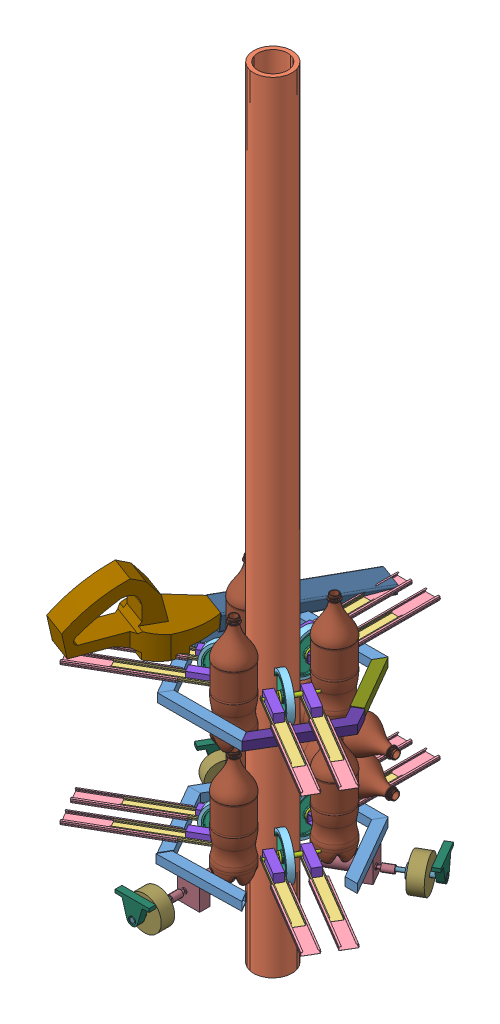
SolidWorks assembly hybrid_final2, configuration Default. Lengths in mm.
Overall size (1377.45 2307.62 1056.72).
117 component instances, 17 part files, 63 mates.
Components (placement in the parent):
- Part1-1: Part1 [Default] at (62.7195 89.3412 215.5234) size (250 25.4 31.11)
- Part1-2: Part1 [Default] at (-99.5841 89.3412 82.0449) x (0.5 0 0.866025) z (-0.866025 0 0.5) size (250 25.4 31.11)
- Part1-3: Part1 [Default] at (62.7195 -320.6588 215.5234) size (250 25.4 31.11) (hidden)
- Part1-5: Part1 [Default] at (293.911 -320.6588 -65.5947) x (-0.5 0 -0.866025) z (0.866025 0 -0.5) size (250 25.4 31.11)
- Part1-6: Part1 [Default] at (-65.1402 -320.6588 -125.2534) x (-0.5 0 0.866025) z (-0.866025 0 -0.5) size (250 25.4 31.11)
- Part1-9: Part1 [Default] at (131.6074 -320.6588 -199.0732) x (-1 0 0) z (0 0 -1) size (250 25.4 31.11)
- Part1-10: Part1 [Default] at (-65.1402 89.3412 -125.2534) x (-0.5 0 0.866025) z (-0.866025 0 -0.5) size (250 25.4 31.11)
- Part1-11: Part1 [Default] at (131.6074 89.3412 -199.0732) x (-1 0 0) z (0 0 -1) size (250 25.4 31.11)
- Part1-12: Part1 [Default] at (-99.5841 -320.6588 82.0449) x (0.5 0 0.866025) z (-0.866025 0 0.5) size (250 25.4 31.11)
- pole-1: pole [Default] at (97.1935 -621.7615 8.2424) x (-0.198927 0 0.980014) z (-0.980014 0 -0.198927) size (114 2307.62 114)
- wheel_sys_pole-1: wheel_sys_pole [Default] at (-216.3042 -39.4819 -61.3313) x (0 0 -1) z (1 0 0) size (427.17 170.74 131.58)
  - slider-1: slider [Default] at (295.7545 161.9821 248.2331) size (359 10.5 44.88)
    - inner slider-1: inner slider [Default] at (-151.895 -7.559 16.8408) size (254 10.3 34.88)
    - outer slider-1: outer slider [Default] at (-46.895 -7.759 16.5388) size (254 10.08 44.88)
  - wheelwithaxle_pole-1: wheelwithaxle_pole [Default] at (804.7391 46.5563 384.5567) x (0.829197 -0.558957 0) z (-0.558957 -0.829197 0) size (123 127 123)
    - rim-1: rim [Default] at (-711.4248 -76.2879 334.1654) size (123 19 123)
    - wheel_inner_pole-1: wheel_inner_pole [Default] at (-711.4248 -76.2879 334.1654) size (107 19 107)
    - wheel axle-1: wheel axle [Default] at (-713.6031 -81.7741 334.1654) size (28 127 28)
  - slider-2: slider [Default] at (295.7545 161.9821 330.8673) size (359 10.5 44.88)
    - inner slider-1: inner slider [Default] at (-151.895 -7.559 16.8408) size (254 10.3 34.88)
    - outer slider-1: outer slider [Default] at (-46.895 -7.759 16.5388) size (254 10.08 44.88)
  - support-1: support [Default] at (-18.9561 167.1231 347.1618) x (0 -1 0) z (0 0 1) size (25 90.2 25)
  - support-2: support [Default] at (-18.9561 167.1231 265.119) x (0 -1 0) z (0 0 1) size (25 90.2 25)
- wheel_sys_pole-8: wheel_sys_pole [Default] at (198.0796 -39.4819 322.1299) x (-0.866025 0 0.5) z (-0.5 0 -0.866025) size (427.17 170.74 131.58)
  - slider-1: slider [Default] at (295.7545 161.9821 248.2331) size (359 10.5 44.88)
    - inner slider-1: inner slider [Default] at (-151.895 -7.559 16.8408) size (254 10.3 34.88)
    - outer slider-1: outer slider [Default] at (-46.895 -7.759 16.5388) size (254 10.08 44.88)
  - wheelwithaxle_pole-1: wheelwithaxle_pole [Default] at (804.7391 46.5563 384.5567) x (0.829197 -0.558957 0) z (-0.558957 -0.829197 0) size (123 127 123)
    - rim-1: rim [Default] at (-711.4248 -76.2879 334.1654) size (123 19 123)
    - wheel_inner_pole-1: wheel_inner_pole [Default] at (-711.4248 -76.2879 334.1654) size (107 19 107)
    - wheel axle-1: wheel axle [Default] at (-713.6031 -81.7741 334.1654) size (28 127 28)
  - slider-2: slider [Default] at (295.7545 161.9821 330.8673) size (359 10.5 44.88)
    - inner slider-1: inner slider [Default] at (-151.895 -7.559 16.8408) size (254 10.3 34.88)
    - outer slider-1: outer slider [Default] at (-46.895 -7.759 16.5388) size (254 10.08 44.88)
  - support-1: support [Default] at (-18.9561 167.1231 347.1618) x (0 -1 0) z (0 0 1) size (25 90.2 25)
  - support-2: support [Default] at (-18.9561 167.1231 265.119) x (0 -1 0) z (0 0 1) size (25 90.2 25)
- wheel_sys_pole-10: wheel_sys_pole [Default] at (319.5856 -39.4819 -227.7498) x (0.860202 0 0.509953) z (-0.509953 0 0.860202) size (427.17 170.74 131.58)
  - slider-1: slider [Default] at (295.7545 161.9821 248.2331) size (359 10.5 44.88)
    - inner slider-1: inner slider [Default] at (-151.895 -7.559 16.8408) size (254 10.3 34.88)
    - outer slider-1: outer slider [Default] at (-46.895 -7.759 16.5388) size (254 10.08 44.88)
  - wheelwithaxle_pole-1: wheelwithaxle_pole [Default] at (804.7391 46.5563 384.5567) x (0.829197 -0.558957 0) z (-0.558957 -0.829197 0) size (123 127 123)
    - rim-1: rim [Default] at (-711.4248 -76.2879 334.1654) size (123 19 123)
    - wheel_inner_pole-1: wheel_inner_pole [Default] at (-711.4248 -76.2879 334.1654) size (107 19 107)
    - wheel axle-1: wheel axle [Default] at (-713.6031 -81.7741 334.1654) size (28 127 28)
  - slider-2: slider [Default] at (295.7545 161.9821 330.8673) size (359 10.5 44.88)
    - inner slider-1: inner slider [Default] at (-151.895 -7.559 16.8408) size (254 10.3 34.88)
    - outer slider-1: outer slider [Default] at (-46.895 -7.759 16.5388) size (254 10.08 44.88)
  - support-1: support [Default] at (-18.9561 167.1231 347.1618) x (0 -1 0) z (0 0 1) size (25 90.2 25)
  - support-2: support [Default] at (-18.9561 167.1231 265.119) x (0 -1 0) z (0 0 1) size (25 90.2 25)
- blower_assemb-1: blower_assemb [Default] at (-520.3544 35.9897 11.0958) x (0.347965 0 -0.937507) z (0.937507 0 0.347965) size (835.33 242.61 170.56)
  - blower_handle-1: blower_handle [Default] at (211.986 78.7515 400.2885) size (835.33 223.79 170.56)
  - nozzle-1: nozzle [Default] at (178.078 64.9806 320.83) x (0.993475 -0.11405 0) z (0 0 1) size (410 47.38 80)
- 2l_cola_bottle-1: 2l_cola_bottle [Standard] at (-175.2913 7.0912 -42.2725) size (104.49 326.54 105)
- 2l_cola_bottle-2: 2l_cola_bottle [Standard] at (-41.6978 7.0912 139.5723) size (104.49 326.54 105)
- 2l_cola_bottle-3: 2l_cola_bottle [Standard] at (49.0019 7.0912 -67.887) size (104.49 326.54 105)
- 2l_cola_bottle-6: 2l_cola_bottle [Standard] at (-76.7175 -251.3106 -270.9861) x (0 0.885599 0.464451) z (0 0.464451 -0.885599) size (104.49 326.54 105)
- 2l_cola_bottle-7: 2l_cola_bottle [Standard] at (49.0019 -335.5167 -67.887) size (104.49 326.54 105)
- 2l_cola_bottle-8: 2l_cola_bottle [Standard] at (-175.2543 -335.5167 -45.6556) x (0.999761 0 0.021868) z (-0.021868 0 0.999761) size (104.49 326.54 105)
- 2l_cola_bottle-9: 2l_cola_bottle [Standard] at (-40.9049 -335.5167 123.9293) x (0.994874 0 0.101118) z (-0.101118 0 0.994874) size (104.49 326.54 105)
- 2l_cola_bottle-10: 2l_cola_bottle [Standard] at (-76.7175 -298.0239 -64.0606) x (0 0.514567 -0.85745) z (0 -0.85745 -0.514567) size (104.49 326.54 105)
- wheel_sys_pole-7: wheel_sys_pole [Default] at (-216.3042 -449.4819 -61.3313) x (0 0 -1) z (1 0 0) size (427.17 170.74 131.58)
  - slider-1: slider [Default] at (295.7545 161.9821 248.2331) size (359 10.5 44.88)
    - inner slider-1: inner slider [Default] at (-151.895 -7.559 16.8408) size (254 10.3 34.88)
    - outer slider-1: outer slider [Default] at (-46.895 -7.759 16.5388) size (254 10.08 44.88)
  - wheelwithaxle_pole-1: wheelwithaxle_pole [Default] at (804.7391 46.5563 384.5567) x (0.829197 -0.558957 0) z (-0.558957 -0.829197 0) size (123 127 123)
    - rim-1: rim [Default] at (-711.4248 -76.2879 334.1654) size (123 19 123)
    - wheel_inner_pole-1: wheel_inner_pole [Default] at (-711.4248 -76.2879 334.1654) size (107 19 107)
    - wheel axle-1: wheel axle [Default] at (-713.6031 -81.7741 334.1654) size (28 127 28)
  - slider-2: slider [Default] at (295.7545 161.9821 330.8673) size (359 10.5 44.88)
    - inner slider-1: inner slider [Default] at (-151.895 -7.559 16.8408) size (254 10.3 34.88)
    - outer slider-1: outer slider [Default] at (-46.895 -7.759 16.5388) size (254 10.08 44.88)
  - support-1: support [Default] at (-18.9561 167.1231 347.1618) x (0 -1 0) z (0 0 1) size (25 90.2 25)
  - support-2: support [Default] at (-18.9561 167.1231 265.119) x (0 -1 0) z (0 0 1) size (25 90.2 25)
- wheel_sys_pole-9: wheel_sys_pole [Default] at (198.0796 -449.4819 322.1299) x (-0.866025 0 0.5) z (-0.5 0 -0.866025) size (427.17 170.74 131.58)
  - slider-1: slider [Default] at (295.7545 161.9821 248.2331) size (359 10.5 44.88)
    - inner slider-1: inner slider [Default] at (-151.895 -7.559 16.8408) size (254 10.3 34.88)
    - outer slider-1: outer slider [Default] at (-46.895 -7.759 16.5388) size (254 10.08 44.88)
  - wheelwithaxle_pole-1: wheelwithaxle_pole [Default] at (804.7391 46.5563 384.5567) x (0.829197 -0.558957 0) z (-0.558957 -0.829197 0) size (123 127 123)
    - rim-1: rim [Default] at (-711.4248 -76.2879 334.1654) size (123 19 123)
    - wheel_inner_pole-1: wheel_inner_pole [Default] at (-711.4248 -76.2879 334.1654) size (107 19 107)
    - wheel axle-1: wheel axle [Default] at (-713.6031 -81.7741 334.1654) size (28 127 28)
  - slider-2: slider [Default] at (295.7545 161.9821 330.8673) size (359 10.5 44.88)
    - inner slider-1: inner slider [Default] at (-151.895 -7.559 16.8408) size (254 10.3 34.88)
    - outer slider-1: outer slider [Default] at (-46.895 -7.759 16.5388) size (254 10.08 44.88)
  - support-1: support [Default] at (-18.9561 167.1231 347.1618) x (0 -1 0) z (0 0 1) size (25 90.2 25)
  - support-2: support [Default] at (-18.9561 167.1231 265.119) x (0 -1 0) z (0 0 1) size (25 90.2 25)
- wheel_sys_pole-11: wheel_sys_pole [Default] at (319.5856 -449.4819 -227.7498) x (0.860202 0 0.509953) z (-0.509953 0 0.860202) size (427.17 170.74 131.58)
  - slider-1: slider [Default] at (295.7545 161.9821 248.2331) size (359 10.5 44.88)
    - inner slider-1: inner slider [Default] at (-151.895 -7.559 16.8408) size (254 10.3 34.88)
    - outer slider-1: outer slider [Default] at (-46.895 -7.759 16.5388) size (254 10.08 44.88)
  - wheelwithaxle_pole-1: wheelwithaxle_pole [Default] at (804.7391 46.5563 384.5567) x (0.829197 -0.558957 0) z (-0.558957 -0.829197 0) size (123 127 123)
    - rim-1: rim [Default] at (-711.4248 -76.2879 334.1654) size (123 19 123)
    - wheel_inner_pole-1: wheel_inner_pole [Default] at (-711.4248 -76.2879 334.1654) size (107 19 107)
    - wheel axle-1: wheel axle [Default] at (-713.6031 -81.7741 334.1654) size (28 127 28)
  - slider-2: slider [Default] at (295.7545 161.9821 330.8673) size (359 10.5 44.88)
    - inner slider-1: inner slider [Default] at (-151.895 -7.559 16.8408) size (254 10.3 34.88)
    - outer slider-1: outer slider [Default] at (-46.895 -7.759 16.5388) size (254 10.08 44.88)
  - support-1: support [Default] at (-18.9561 167.1231 347.1618) x (0 -1 0) z (0 0 1) size (25 90.2 25)
  - support-2: support [Default] at (-18.9561 167.1231 265.119) x (0 -1 0) z (0 0 1) size (25 90.2 25)
- Wheel_sys_lower-1: Wheel_sys_lower [Default] at (-267.2535 -516.7508 -98.9365) x (-0.584128 -0.028115 0.811174) z (-0.233785 0.962874 -0.134976) size (141.79 280.46 162.59)
  - omni-1: omni [Default] at (-77.0455 69.9199 150.3063) x (0.545954 -0.173862 -0.819577) z (0.831792 0.229571 0.50539) size (100 40 100)
  - motor-1: motor [Default] at (-76.5038 184.1966 116.3052) x (0.994562 0.104149 0) z (-0.028115 0.268484 0.962874) size (65 158 65)
  - shaft-1: shaft [Default] at (-87.3634 168.4493 120.2645) x (-0.994562 -0.104149 0) z (-0.028115 0.268484 0.962874) size (38.13 139.7 38.13)
  - support_lower_wheel-1: support_lower_wheel [Default] at (-76.2241 54.2728 211.6456) x (0.994562 0.104149 0) z (-0.100283 0.957637 -0.269952) size (100 70 20)
- Wheel_sys_lower-2: Wheel_sys_lower [Default] at (370.3499 -516.7508 -256.9523) x (-0.410434 -0.028115 -0.911457) z (0.233785 0.962874 -0.134976) size (141.79 280.46 162.59)
  - omni-1: omni [Default] at (-77.0455 69.9199 150.3063) x (0.545954 -0.173862 -0.819577) z (0.831792 0.229571 0.50539) size (100 40 100)
  - motor-1: motor [Default] at (-76.5038 184.1966 116.3052) x (0.994562 0.104149 0) z (-0.028115 0.268484 0.962874) size (65 158 65)
  - shaft-1: shaft [Default] at (-87.3634 168.4493 120.2645) x (-0.994562 -0.104149 0) z (-0.028115 0.268484 0.962874) size (38.13 139.7 38.13)
  - support_lower_wheel-1: support_lower_wheel [Default] at (-76.2241 54.2728 211.6456) x (0.994562 0.104149 0) z (-0.100283 0.957637 -0.269952) size (100 70 20)
- Wheel_sys_lower-3: Wheel_sys_lower [Default] at (121.5672 -516.7508 377.4002) x (0.994562 -0.028115 0.100283) z (0 0.962874 0.269952) size (141.79 280.46 162.59)
  - omni-1: omni [Default] at (-77.0455 69.9199 150.3063) x (0.545954 -0.173862 -0.819577) z (0.831792 0.229571 0.50539) size (100 40 100)
  - motor-1: motor [Default] at (-76.5038 184.1966 116.3052) x (0.994562 0.104149 0) z (-0.028115 0.268484 0.962874) size (65 158 65)
  - shaft-1: shaft [Default] at (-87.3634 168.4493 120.2645) x (-0.994562 -0.104149 0) z (-0.028115 0.268484 0.962874) size (38.13 139.7 38.13)
  - support_lower_wheel-1: support_lower_wheel [Default] at (-76.2241 54.2728 211.6456) x (0.994562 0.104149 0) z (-0.100283 0.957637 -0.269952) size (100 70 20)
- Part1-14: Part1 [Default] at (62.576 -320.6588 218.486) x (0.999828 0 -0.018571) z (0.018571 0 0.999828) size (250 25.4 31.11)
- gate_normal-1: gate_normal [Default] at (271.7443 114.7412 -67.3862) x (0.5 0 0.866025) z (0.866025 0 -0.5) size (192.04 25.4 31.1)
- gate_extended-1: gate_extended [Default] at (264.9057 89.3412 106.8836) x (0.509953 0 -0.860202) z (0.860202 0 0.509953) size (278.98 25.4 65.74)
Mates (geometry in assembly coordinates):
- Coincident3: coincident aligned: plane of Part1-1 through (62.7195 114.7412 215.5234) normal (0 1 0); plane of Part1-10 through (-65.1402 114.7412 -125.2534) normal (0 1 0)
- Coincident8: coincident anti-aligned: plane of Part1-10 through (-27.8366 114.7412 -208.2813) normal (0.866025 0 -0.5); plane of Part1-11 through (-27.8366 114.7412 -208.2813) normal (-0.866025 0 0.5)
- Coincident9: coincident aligned: line of Part1-10 through (-27.8366 114.7412 -208.2813) axis (0 -1 0); line of Part1-11 through (-27.8366 114.7412 -208.2813) axis (0 -1 0)
- Coincident10: coincident anti-aligned: plane of Part1-2 through (-152.8366 114.7412 8.2251) normal (0 0 -1); plane of Part1-10 through (-152.8366 114.7412 8.2251) normal (0 0 1)
- Coincident11: coincident aligned: line of Part1-2 through (-152.8366 114.7412 8.2251) axis (0 -1 0); line of Part1-10 through (-152.8366 114.7412 8.2251) axis (0 -1 0)
- Coincident12: coincident anti-aligned: plane of Part1-1 through (-27.8366 114.7412 224.7314) normal (-0.866025 0 -0.5); plane of Part1-2 through (-27.8366 114.7412 224.7314) normal (0.866025 0 0.5)
- Coincident13: coincident aligned: line of Part1-1 through (-27.8366 114.7412 224.7314) axis (0 -1 0); line of Part1-2 through (-27.8366 114.7412 224.7314) axis (0 -1 0)
- Coincident16: coincident aligned: plane of Part1-6 through (-65.1402 -295.2588 -125.2534) normal (0 1 0); plane of Part1-12 through (-99.5841 -295.2588 82.0449) normal (0 1 0)
- Coincident17: coincident aligned: plane of Part1-5 through (293.911 -295.2588 -65.5947) normal (0 1 0); plane of Part1-9 through (131.6074 -295.2588 -199.0732) normal (0 1 0)
- Coincident18: coincident aligned: plane of Part1-5 through (293.911 -295.2588 -65.5947) normal (0 1 0); plane of Part1-6 through (-65.1402 -295.2588 -125.2534) normal (0 1 0)
- Coincident19: coincident aligned: plane of Part1-3 through (62.7195 -295.2588 215.5234) normal (0 1 0); plane of Part1-6 through (-65.1402 -295.2588 -125.2534) normal (0 1 0)
- Coincident21: coincident anti-aligned: plane of Part1-5 through (222.1634 -295.2588 -208.2813) normal (-0.866025 0 -0.5); plane of Part1-9 through (222.1634 -295.2588 -208.2813) normal (0.866025 0 0.5)
- Coincident22: coincident aligned: line of Part1-5 through (222.1634 -295.2588 -208.2813) axis (0 -1 0); line of Part1-9 through (222.1634 -295.2588 -208.2813) axis (0 -1 0)
- Coincident23: coincident anti-aligned: plane of Part1-6 through (-27.8366 -295.2588 -208.2813) normal (0.866025 0 -0.5); plane of Part1-9 through (-27.8366 -295.2588 -208.2813) normal (-0.866025 0 0.5)
- Coincident24: coincident aligned: line of Part1-6 through (-27.8366 -295.2588 -208.2813) axis (0 -1 0); line of Part1-9 through (-27.8366 -295.2588 -208.2813) axis (0 -1 0)
- Coincident25: coincident anti-aligned: plane of Part1-6 through (-152.8366 -295.2588 8.2251) normal (0 0 1); plane of Part1-12 through (-152.8366 -295.2588 8.2251) normal (0 0 -1)
- Coincident26: coincident aligned: line of Part1-6 through (-152.8366 -295.2588 8.2251) axis (0 -1 0); line of Part1-12 through (-152.8366 -295.2588 8.2251) axis (0 -1 0)
- Coincident27: coincident anti-aligned: plane of Part1-3 through (-27.8366 -295.2588 224.7314) normal (-0.866025 0 -0.5); plane of Part1-12 through (-27.8366 -295.2588 224.7314) normal (0.866025 0 0.5)
- Coincident28: coincident aligned: line of Part1-3 through (-27.8366 -295.2588 224.7314) axis (0 -1 0); line of Part1-12 through (-27.8366 -295.2588 224.7314) axis (0 -1 0)
- Distance3: distance = 410 mm aligned: plane of Part1-1 through (62.7195 114.7412 215.5234) normal (0 1 0); plane of Part1-3 through (62.7195 -295.2588 215.5234) normal (0 1 0)
- Coincident36: coincident aligned: plane of Part1-6 through (-9.8761 -295.2588 -177.1727) normal (0.866025 0 0.5); plane of Part1-10 through (-9.8761 114.7412 -177.1727) normal (0.866025 0 0.5)
- Coincident37: coincident aligned: plane of Part1-9 through (204.2029 -295.2588 -177.1727) normal (0 0 1); plane of Part1-11 through (204.2029 114.7412 -177.1727) normal (0 0 1)
- Perpendicular3: perpendicular: axis of pole-1 through (97.1935 1685.8585 8.2424) axis (0 -1 0); line of assembly
- Distance22: distance = 1685.8585 mm aligned: plane of pole-1 through (97.1935 1685.8585 8.2424) normal (0 1 0); plane of assembly through (0 0 0) normal (0 1 0)
- Coincident82: coincident: axis of pole-1 through (97.1935 1685.8585 8.2424) axis (0 -1 0); plane of assembly
- Coincident87: coincident anti-aligned: plane of Part1-10 through (-65.1402 114.7412 -125.2534) normal (0 1 0); plane of wheel_sys_pole-1/slider-2/outer slider-1 through (131.1019 114.7412 -310.1909) normal (0 -1 0)
- Coincident88: coincident anti-aligned: plane of Part1-11 through (131.6074 114.7412 -199.0732) normal (0 1 0); plane of wheel_sys_pole-8/slider-2/outer slider-1 through (-191.1421 114.7412 145.6972) normal (0 -1 0)
- Coincident89: coincident aligned: plane of Part1-11 through (204.2029 114.7412 -177.1727) normal (0 0 1); plane of wheel_sys_pole-1/slider-1/outer slider-1 through (26.9676 114.9412 -177.1727) normal (0 0 1)
- Coincident90: coincident aligned: plane of Part1-2 through (-116.9155 114.7412 8.2251) normal (0.866025 0 -0.5); plane of wheel_sys_pole-8/slider-1/outer slider-1 through (-23.8779 114.9412 169.371) normal (0.866025 0 -0.5)
- Distance26: distance = 83.0998 mm: point of Part1-10; line of wheel_sys_pole-8/slider-2/inner slider-1 through (6.5866 114.9412 12.1372) axis (-0.866025 0 0.5)
- Coincident96: coincident anti-aligned: plane of Part1-1 through (62.7195 114.7412 215.5234) normal (0 1 0); plane of blower_assemb-1/blower_handle-1 through (-71.3172 114.7412 -48.3561) normal (0 -1 0)
- Coincident98: coincident aligned: plane of 2l_cola_bottle-8 through (-32.889 -3.2315 -42.5415) normal (0 1 0); plane of 2l_cola_bottle-9 through (100.7646 -3.2315 138.3285) normal (0 1 0)
- Coincident99: coincident aligned: plane of 2l_cola_bottle-7 through (191.4012 -3.2315 -67.887) normal (0 1 0); plane of 2l_cola_bottle-8 through (-32.889 -3.2315 -42.5415) normal (0 1 0)
- Coincident100: coincident: plane of 2l_cola_bottle-2 through (100.7015 339.3764 139.5723) normal (0 1 0); circle of 2l_cola_bottle-1
- Coincident101: coincident aligned: plane of 2l_cola_bottle-2 through (100.7015 339.3764 139.5723) normal (0 1 0); plane of 2l_cola_bottle-3 through (191.4012 339.3764 -67.887) normal (0 1 0)
- Coincident102: coincident aligned: axis of 2l_cola_bottle-2 through (113.0015 241.9911 139.5723) axis (0 1 0); axis of 2l_cola_bottle-9 through (113.0015 -144.9684 139.5723) axis (0 1 0)
- Coincident103: coincident aligned: axis of 2l_cola_bottle-1 through (-20.5919 117.3724 -42.2725) axis (0 1 0); axis of 2l_cola_bottle-8 through (-20.5919 -144.9684 -42.2725) axis (0 1 0)
- Coincident104: coincident aligned: axis of 2l_cola_bottle-3 through (203.7012 117.3724 -67.887) axis (0 1 0); axis of 2l_cola_bottle-7 through (203.7012 -144.9684 -67.887) axis (0 1 0)
- Coincident110: coincident aligned: plane of 2l_cola_bottle-6 through (255.5676 -125.2019 -204.8486) normal (1 0 0); plane of 2l_cola_bottle-10 through (255.5676 -224.7499 -186.1609) normal (1 0 0)
- Distance31: distance = 104.14 mm: axis of 2l_cola_bottle-6 through (113.8308 -114.3091 -199.1359) axis (1 0 0); axis of 2l_cola_bottle-10 through (-61.8598 -218.4207 -196.7075) axis (1 0 0)
- Coincident111: coincident anti-aligned: plane of Part1-3 through (62.7195 -320.6588 215.5234) normal (0 -1 0); plane of Wheel_sys_lower-3/motor-1 through (32.1634 -320.6588 194.7314) normal (0 1 0)
- Coincident112: coincident aligned: plane of Wheel_sys_lower-2/motor-1 through (256.856 -320.6588 -88.192) normal (0 1 0); plane of Wheel_sys_lower-3/motor-1 through (32.1634 -320.6588 194.7314) normal (0 1 0)
- Coincident113: coincident aligned: plane of Wheel_sys_lower-1/motor-1 through (-64.3558 -320.6588 -85.0281) normal (0 1 0); plane of Wheel_sys_lower-2/motor-1 through (256.856 -320.6588 -88.192) normal (0 1 0)
- Parallel1: parallel anti-aligned: plane of Part1-6 through (-27.8366 -295.2588 -208.2813) normal (-0.866025 0 -0.5); plane of Wheel_sys_lower-1/motor-1 through (-6.9937 -353.1588 -14.3823) normal (0.866025 0 0.5)
- Coincident115: coincident aligned: line of Part1-6 through (-27.8366 -320.6588 -208.2813) axis (-0.5 0 0.866025); line of Wheel_sys_lower-1/motor-1 through (-90.3366 -320.6588 -100.0281) axis (-0.5 0 0.866025)
- Distance32: distance = 125 mm: line of Wheel_sys_lower-1/motor-1 through (-90.3366 -385.6588 -100.0281) axis (0 1 0); line of Part1-6 through (-27.8366 -295.2588 -208.2813) axis (0 -1 0)
- Parallel3: parallel aligned: line of Part1-5 through (347.1634 -295.2588 8.2251) axis (-0.5 0 -0.866025); line of Wheel_sys_lower-2/motor-1 through (282.8367 -320.6588 -103.192) axis (-0.5 0 -0.866025)
- Distance33: distance = 125 mm: line of Wheel_sys_lower-2/motor-1 through (256.856 -385.6588 -88.192) axis (0 1 0); line of Part1-9 through (222.1634 -295.2588 -208.2813) axis (0 -1 0)
- Coincident120: coincident aligned: plane of Part1-5 through (347.1634 -295.2588 8.2251) normal (0.866025 0 -0.5); plane of Wheel_sys_lower-2/motor-1 through (266.5867 -353.1588 -131.3378) normal (0.866025 0 -0.5)
- Coincident121: coincident aligned: plane of Part1-3 through (-27.8366 -295.2588 224.7314) normal (0 0 1); plane of Wheel_sys_lower-3/motor-1 through (64.6634 -353.1588 224.7314) normal (0 0 1)
- Distance34: distance = 125 mm: line of ? through (222.1634 -295.2588 224.7314) axis (0 -1 0); line of Wheel_sys_lower-3/motor-1 through (97.1634 -320.6588 224.7314) axis (0 -1 0)
- Distance37: distance = 224.6352 mm: plane of 2l_cola_bottle-2 through (100.7015 339.3764 139.5723) normal (0 1 0); plane of Part1-1 through (62.7195 114.7412 215.5234) normal (0 1 0)
- Coincident122: coincident: plane of ? through (259.0337 -295.2588 141.5102) normal (0 1 0); plane of Part1-14 through (62.6737 -295.2588 216.3547) normal (0 1 0)
- Coincident123: coincident: plane of ? through (222.1634 -295.2588 224.7314) normal (-0.863407 0 0.504508); plane of Part1-14
- Coincident124: coincident aligned: line of ? through (222.1634 -295.2588 224.7314) axis (0 -1 0); line of Part1-14 through (222.1634 -295.2588 224.7314) axis (0 -1 0)
- Coincident125: coincident aligned: plane of Part1-11 through (131.6074 114.7412 -199.0732) normal (0 1 0); plane of gate_normal-1 through (271.7443 114.7412 -67.3862) normal (0 1 0)
- Coincident126: coincident anti-aligned: plane of Part1-11 through (222.1634 114.7412 -208.2813) normal (0.866025 0 0.5); plane of gate_normal-1 through (173.5493 89.3412 -124.0791) normal (-0.866025 0 -0.5)
- Coincident127: coincident anti-aligned: line of Part1-11 through (222.1634 114.7412 -208.2813) axis (0 -1 0); line of gate_normal-1 through (222.1634 89.3412 -208.2813) axis (0 1 0)
- Coincident128: coincident aligned: plane of Part1-1 through (62.7195 114.7412 215.5234) normal (0 1 0); plane of gate_extended-1 through (264.9057 114.7412 106.8836) normal (0 1 0)
- Coincident129: coincident aligned: line of Part1-1 through (222.1634 114.7412 224.7314) axis (0 -1 0); line of gate_extended-1 through (222.1634 114.7412 224.7314) axis (0 -1 0)
- Coincident130: coincident anti-aligned: plane of wheel_sys_pole-10/slider-1/outer slider-1 through (398.6339 114.7412 126.9142) normal (0 -1 0); plane of gate_extended-1 through (264.9057 114.7412 106.8836) normal (0 1 0)
- Coincident131: coincident aligned: plane of wheel_sys_pole-10/slider-2/outer slider-1 through (253.0358 114.9412 111.669) normal (-0.860202 0 -0.509953); plane of gate_extended-1 through (258.2218 114.7412 102.9212) normal (-0.860202 0 -0.509953)
- Distance38: distance = 70 mm: line of wheel_sys_pole-10/slider-2/outer slider-1 through (231.1078 114.7412 148.6577) axis (0.860202 0 0.509953); line of Part1-1 through (222.1634 114.7412 224.7314) axis (0 -1 0)
